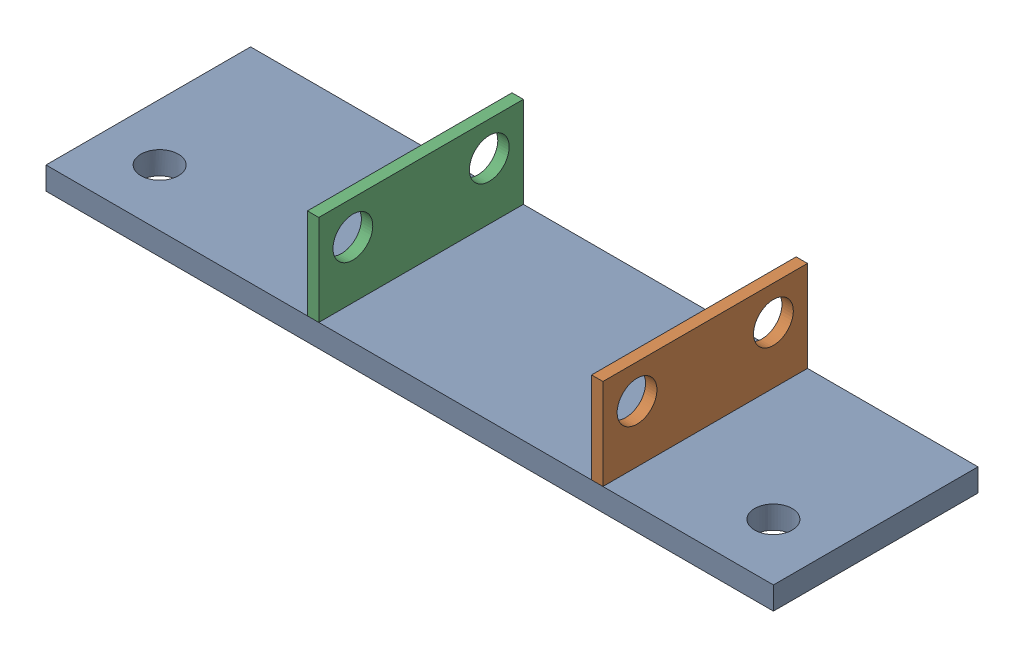
SolidWorks assembly Cam_Support_Ass, configuration Default. Lengths in mm.
Overall size (406.4 63.5 114.3).
3 component instances, 2 part files, 0 mates.
Components (placement in the parent):
- 01-020-00-0-1: 01-020-00-0 [Default] at (-221.5578 -37.3604 106.9552) size (406.4 12.7 114.3)
- Cam Support Tab-1: Cam Support Tab [Default] at (83.2422 -24.6604 106.9552) x (0 1 0) z (-1 0 0) size (50.8 114.3 6.35)
- Cam Support Tab-2: Cam Support Tab [Default] at (-75.5078 -24.6604 106.9552) x (0 1 0) z (-1 0 0) size (50.8 114.3 6.35)
